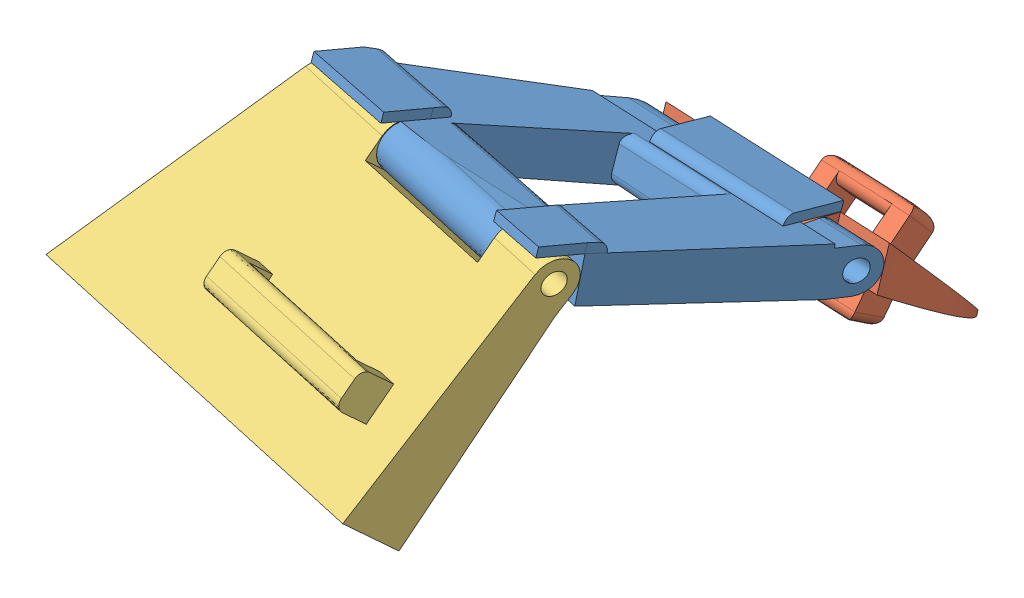
SolidWorks assembly Ear (1), configuration Default. Lengths in mm.
Overall size (78.95 36.05 85).
3 component instances, 3 part files, 4 mates.
Components (placement in the parent):
- Ear2(1)-1: Ear2(1) [Default] at (-0.6496 -5.1371 2.923) x (0.999066 -0.042994 0.004201) z (0.004201 0.193474 0.981096) size (52.77 10.59 40.28)
- Ear1(1)-1: Ear1(1) [Default] at (-0.6392 -4.8481 3.4093) x (0.999066 -0.042994 0.004201) z (0.006579 0.247545 0.968854) size (36.64 18.86 27.5)
- Ear3(1)-1: Ear3(1) [Default] at (-24.9809 3.7092 16.8996) x (0.976187 0 0.21693) z (-0.143392 -0.750382 0.645264) size (58.54 14.04 35.29)
Mates (geometry in assembly coordinates):
- Concentric1: concentric aligned: cylinder of Ear2(1)-1 through (27.415 2.5998 -1.7806) axis (-0.999066 0.042994 -0.004201) radius 1.5; circle of Ear1(1)-1
- Coincident1: coincident anti-aligned: plane of Ear2(1)-1 through (0.4425 19.7591 -1.9912) normal (0.999066 -0.042994 0.004201); plane of Ear1(1)-1 through (0.4453 19.7371 -2.8797) normal (-0.999066 0.042994 -0.004201)
- Concentric2: concentric anti-aligned: circle of Ear2(1)-1; circle of Ear3(1)-1
- Coincident2: coincident anti-aligned: plane of Ear2(1)-1 through (7.0287 25.7365 29.7547) normal (0.976187 0 0.21693); plane of Ear3(1)-1 through (6.1773 12.104 33.5859) normal (-0.976187 0 -0.21693)
